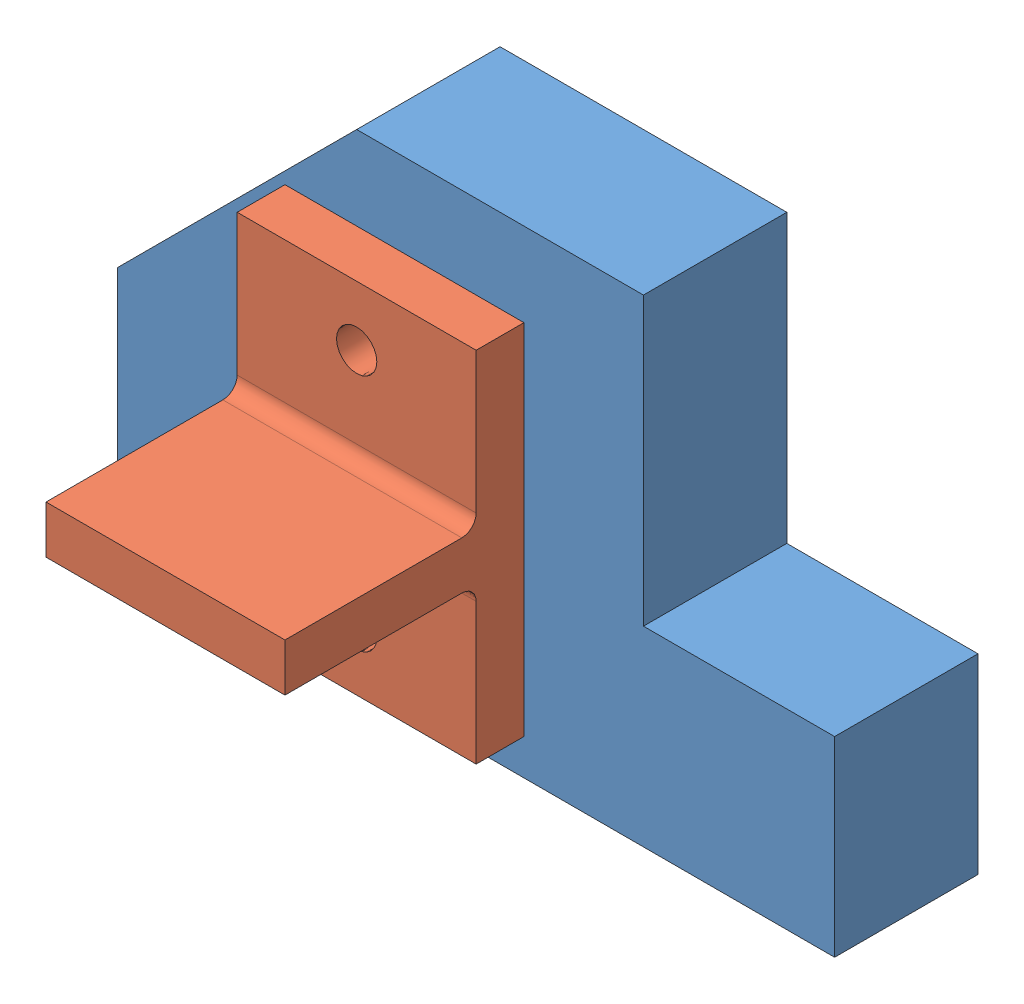
SolidWorks assembly E1_S1_AVA_E, configuration Predeterminado. Lengths in mm.
Overall size (150 100 80).
2 component instances, 2 part files, 3 mates.
Components (placement in the parent):
- E1_S1_AVA_P2-1: E1_S1_AVA_P2 [Predeterminado] at (-82.9774 -42.3746 135) size (150 100 30)
- E1_S1_AVA_P1-1: E1_S1_AVA_P1 [Predeterminado] at (-22.9774 2.6254 165) size (50 75 50)
Mates (geometry in assembly coordinates):
- Concéntrica1: concentric anti-aligned: cylinder of E1_S1_AVA_P2-1 through (-22.9774 27.6254 165) axis (0 0 1) radius 4.2164; cylinder of E1_S1_AVA_P1-1 through (-22.9774 27.6254 165) axis (0 0 -1) radius 4.2164
- Concéntrica2: concentric anti-aligned: cylinder of E1_S1_AVA_P2-1 through (-22.9774 -22.3746 165) axis (0 0 1) radius 4.2164; cylinder of E1_S1_AVA_P1-1 through (-22.9774 -22.3746 165) axis (0 0 -1) radius 4.2164
- Coincidente1: coincident anti-aligned: plane of E1_S1_AVA_P2-1 through (-82.9774 -42.3746 165) normal (0 0 1); plane of E1_S1_AVA_P1-1 through (-22.9774 2.6254 165) normal (0 0 -1)
